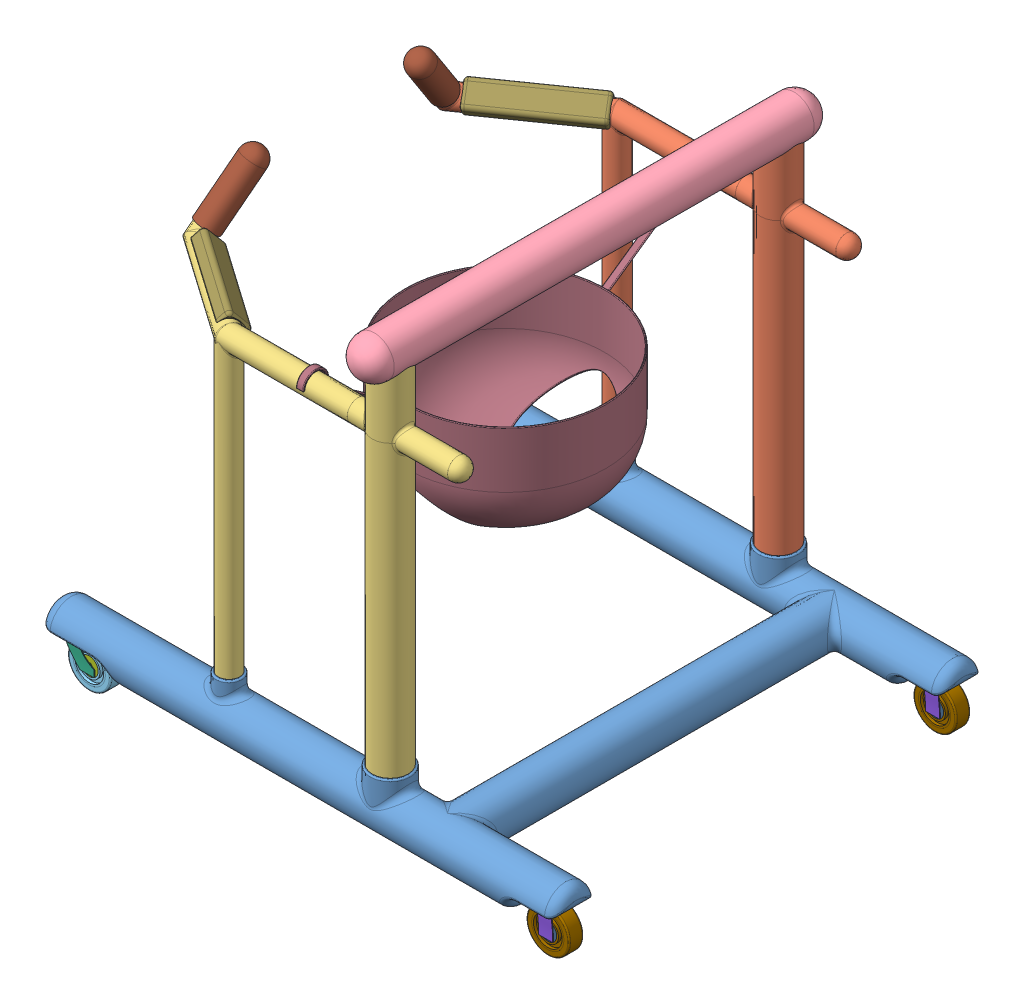
SolidWorks assembly Assem V2 Prototype, configuration Default. Lengths in mm.
Overall size (922.93 824.12 813.04).
41 component instances, 14 part files, 60 mates.
Components (placement in the parent):
- Base V5-1: Base V5 [Default] at (-126.4785 391.078 1010.3536) size (918.71 101.65 765.3)
- Side Left-1: Side Left [Default] at (402.939 968.928 324.5536) x (-1 0 0) z (0 0 -1) size (623.13 766.95 244.49)
- MirrorSide Left-3: MirrorSide Left [Default] at (400.5715 968.928 1010.3536) x (-1 0 0) z (0 0 -1) size (623.13 766.95 244.49)
- TopBarSupport-1: TopBarSupport [Default] at (457.5023 1094.5251 1073.8533) x (0.003452 0 -0.999994) z (0.999994 0 0.003452) size (812.8 71.12 71.12)
- Assem2 Front Wheel-1: Assem2 Front Wheel [Default] at (12.5906 315.4768 322.3492) x (0 0 1) z (-0.999997 0.002364 0) size (53.34 80.1 80.32)
  - Front Wheel-1: Front Wheel [Default] at (-10.3636 34.7825 75.6515) size (25.4 76.2 76.2)
  - Front Wheel Mountv2-1: Front Wheel Mountv2 [Default] at (18.654 50.0525 62.9876) x (1 0 0) z (0 -0.002364 0.999997) size (53.34 52.12 57.51)
  - Front Wheel BearingSet-1: Front Wheel BearingSet [Default] at (-10.3636 34.7825 75.6515) x (0 0.002364 -0.999997) z (1 0 0) size (31.75 31.75 25.4)
- Assem2 Front Wheel-2: Assem2 Front Wheel [Default] at (12.5906 315.4768 1008.1492) x (0 0 1) z (-0.999997 0.002364 0) size (53.34 80.1 80.32)
  - Front Wheel-1: Front Wheel [Default] at (-10.3636 34.7825 75.6515) size (25.4 76.2 76.2)
  - Front Wheel Mountv2-1: Front Wheel Mountv2 [Default] at (18.654 50.0525 62.9876) x (1 0 0) z (0 -0.002364 0.999997) size (53.34 52.12 57.51)
  - Front Wheel BearingSet-1: Front Wheel BearingSet [Default] at (-10.3636 34.7825 75.6515) x (0 0.002364 -0.999997) z (1 0 0) size (31.75 31.75 25.4)
- Assem2 Back Wheel-1: Assem2 Back Wheel [Default] at (706.4816 333.8846 330.834) x (0 0 -1) z (1 0 0) size (53.34 88.94 88.94)
  - Back Wheel Mountv2-1: Back Wheel Mountv2 [Default] at (22.7299 31.7935 30.6399) size (53.34 52.07 26.61)
  - Back Wheel-1: Back Wheel [Default] at (-6.5311 16.5535 43.3399) x (1 0 0) z (0 -0.184287 0.982872) size (25.4 76.2 76.2)
  - BackWheel Bairing Set-1: BackWheel Bairing Set [Default] at (18.8689 16.5535 43.3399) x (0 0 1) z (-1 0 0) size (31.75 31.75 25.4)
- Assem2 Back Wheel-2: Assem2 Back Wheel [Default] at (706.4816 333.8846 1016.634) x (0 0 -1) z (1 0 0) size (53.34 88.94 88.94)
  - Back Wheel Mountv2-1: Back Wheel Mountv2 [Default] at (22.7299 31.7935 30.6399) size (53.34 52.07 26.61)
  - Back Wheel-1: Back Wheel [Default] at (-6.5311 16.5535 43.3399) x (1 0 0) z (0 -0.184287 0.982872) size (25.4 76.2 76.2)
  - BackWheel Bairing Set-1: BackWheel Bairing Set [Default] at (18.8689 16.5535 43.3399) x (0 0 1) z (-1 0 0) size (31.75 31.75 25.4)
- Handle Covering v1-1: Handle Covering v1 [Default] at (-2.516 968.928 448.3888) x (0.979122 -0.193427 -0.062493) z (-0.062493 -0.578988 0.812937) size (43.18 127 43.18)
- Handle Covering v1-2: Handle Covering v1 [Default] at (-4.8834 968.928 886.5185) x (0.979122 -0.193427 0.062493) z (0.062493 0.578988 0.812937) size (43.18 127 43.18)
- Arm Covering v1-1: Arm Covering v1 [Default] at (88.3616 968.928 951.8093) x (0.819152 0 0.573576) z (-0.390769 0.732018 0.558076) size (190.83 24.3 45.72)
- Arm Covering v1-2: Arm Covering v1 [Default] at (92.2038 968.928 382.0653) x (0.819152 0 -0.573576) z (0.446291 -0.62816 0.637369) size (190.83 24.3 45.72)
- ChairPiece-1: ChairPiece [Default] at (318.9986 782.9456 667.2302) x (0 0.001708 0.999999) z (-1 0 0) size (730.43 346.85 355.6)
- WheelScrews-1: WheelScrews [Default] at (-97.2541 392.348 301.6936) x (-0.070113 0 0.997539) z (0.997539 0 0.070113) size (3.81 17.78 3.81)
- WheelScrews-2: WheelScrews [Default] at (-79.4885 392.348 301.6936) x (-0.070113 0 0.997539) z (0.997539 0 0.070113) size (3.81 17.78 3.81)
- WheelScrews-3: WheelScrews [Default] at (-79.4739 392.348 347.4136) x (-0.070113 0 0.997539) z (0.997539 0 0.070113) size (3.81 17.78 3.81)
- WheelScrews-4: WheelScrews [Default] at (-97.2685 392.348 347.4136) x (-0.070113 0 0.997539) z (0.997539 0 0.070113) size (3.81 17.78 3.81)
- WheelScrews-5: WheelScrews [Default] at (-79.4739 392.348 1033.2136) x (-0.070113 0 0.997539) z (0.997539 0 0.070113) size (3.81 17.78 3.81)
- WheelScrews-7: WheelScrews [Default] at (-97.2685 392.348 1033.2136) x (-0.070113 0 0.997539) z (0.997539 0 0.070113) size (3.81 17.78 3.81)
- WheelScrews-8: WheelScrews [Default] at (-79.4885 392.348 987.4936) x (-0.070113 0 0.997539) z (0.997539 0 0.070113) size (3.81 17.78 3.81)
- WheelScrews-9: WheelScrews [Default] at (-97.2541 392.348 987.4936) x (-0.070113 0 0.997539) z (0.997539 0 0.070113) size (3.81 17.78 3.81)
- WheelScrews-10: WheelScrews [Default] at (740.9315 392.348 347.4136) x (-0.837169 0 -0.546944) z (-0.546944 0 0.837169) size (3.81 17.78 3.81)
- WheelScrews-11: WheelScrews [Default] at (758.7115 392.348 347.4136) x (-0.837169 0 -0.546944) z (-0.546944 0 0.837169) size (3.81 17.78 3.81)
- WheelScrews-14: WheelScrews [Default] at (758.7115 392.348 301.6936) x (-0.837169 0 -0.546944) z (-0.546944 0 0.837169) size (3.81 17.78 3.81)
- WheelScrews-15: WheelScrews [Default] at (740.9315 392.348 301.6936) x (-0.837169 0 -0.546944) z (-0.546944 0 0.837169) size (3.81 17.78 3.81)
- WheelScrews-16: WheelScrews [Default] at (740.9315 392.348 1033.2136) x (-0.837169 0 -0.546944) z (-0.546944 0 0.837169) size (3.81 17.78 3.81)
- WheelScrews-18: WheelScrews [Default] at (758.7115 392.348 987.4936) x (-0.837169 0 -0.546944) z (-0.546944 0 0.837169) size (3.81 17.78 3.81)
- WheelScrews-19: WheelScrews [Default] at (740.9315 392.348 987.4936) x (-0.837169 0 -0.546944) z (-0.546944 0 0.837169) size (3.81 17.78 3.81)
- WheelScrews-20: WheelScrews [Default] at (758.7115 392.348 1033.2136) x (-0.837169 0 -0.546944) z (-0.546944 0 0.837169) size (3.81 17.78 3.81)
Mates (geometry in assembly coordinates):
- Tangent1: tangent aligned: cylinder of Base V5-1 through (635.5215 391.078 324.5536) axis (-1 0 0) radius 31.75; sphere of Side Left-1
- Concentric1: concentric aligned: cylinder of Base V5-1 through (460.089 352.977 324.5536) axis (0 1 0) radius 31.75; cylinder of Side Left-1 through (460.089 359.328 324.5536) axis (0 1 0) radius 31.75
- Concentric2: concentric anti-aligned: cylinder of Base V5-1 through (174.339 391.078 324.5536) axis (0 1 0) radius 19.05; cylinder of Side Left-1 through (174.339 968.928 324.5536) axis (0 -1 0) radius 19.05
- Tangent2: tangent aligned: cylinder of Base V5-1 through (635.5215 391.078 1010.3536) axis (-1 0 0) radius 31.75; sphere of MirrorSide Left-3
- Concentric3: concentric aligned: cylinder of Base V5-1 through (457.7215 352.977 1010.3536) axis (0 1 0) radius 31.75; cylinder of MirrorSide Left-3 through (457.7215 359.328 1010.3536) axis (0 1 0) radius 31.75
- Concentric4: concentric anti-aligned: cylinder of Base V5-1 through (171.9715 391.078 1010.3536) axis (0 1 0) radius 19.05; cylinder of MirrorSide Left-3 through (171.9715 968.928 1010.3536) axis (0 -1 0) radius 19.05
- Tangent3: tangent aligned: sphere of MirrorSide Left-3; cylinder of TopBarSupport-1 through (460.2205 1094.5251 286.458) axis (-0.003452 0 0.999994) radius 31.75
- Tangent4: tangent aligned: sphere of Side Left-1; cylinder of TopBarSupport-1 through (460.2205 1094.5251 286.458) axis (-0.003452 0 0.999994) radius 31.75
- Concentric5: concentric aligned: cylinder of MirrorSide Left-3 through (457.7215 968.928 1010.3536) axis (0 1 0) radius 31.75; cylinder of TopBarSupport-1 through (457.7215 1058.9641 1010.3536) axis (0 1 0) radius 31.75
- Concentric6: concentric: sphere of Side Left-1; sphere of Handle Covering v1-1
- Concentric7: concentric anti-aligned: cylinder of Side Left-1 through (-10.1378 937.7174 425.5741) axis (0.193427 0.79206 0.578988) radius 19.05; cylinder of Handle Covering v1-1 through (24.5058 1079.5788 529.2735) axis (-0.193427 -0.79206 -0.578988) radius 19.05
- Concentric8: concentric: sphere of MirrorSide Left-3; sphere of Handle Covering v1-2
- Concentric9: concentric anti-aligned: cylinder of MirrorSide Left-3 through (-12.5053 937.7174 909.3332) axis (0.193427 0.79206 -0.578988) radius 19.05; cylinder of Handle Covering v1-2 through (22.1383 1079.5788 805.6338) axis (-0.193427 -0.79206 0.578988) radius 19.05
- Concentric10: concentric aligned: cylinder of MirrorSide Left-3 through (184.1534 968.928 1018.8835) axis (-0.819152 0 -0.573576) radius 19.05; cylinder of Arm Covering v1-1 through (166.3866 968.928 1006.4431) axis (-0.819152 0 -0.573576) radius 19.05
- Concentric11: concentric aligned: cylinder of Side Left-1 through (186.5208 968.928 316.0238) axis (-0.819152 0 0.573576) radius 19.05; cylinder of Arm Covering v1-2 through (170.2288 968.928 327.4316) axis (-0.819152 0 0.573576) radius 19.05
- Coincident1: coincident anti-aligned: plane of Base V5-1 through (-126.4785 392.348 1010.3536) normal (0 -1 0); plane of Assem2 Front Wheel-1/Front Wheel Mountv2-1 through (-50.2785 392.348 341.0032) normal (0 1 0)
- Coincident2: coincident anti-aligned: plane of Base V5-1 through (-101.0785 392.348 297.8836) normal (0 0 1); plane of Assem2 Front Wheel-1/Front Wheel Mountv2-1 through (-50.2785 365.678 297.8836) normal (0 0 -1)
- Coincident3: coincident anti-aligned: plane of Base V5-1 through (-101.0785 392.348 351.2236) normal (1 0 0); plane of Assem2 Front Wheel-1/Front Wheel Mountv2-1 through (-101.0785 392.348 351.2236) normal (-1 0 0)
- Coincident4: coincident anti-aligned: plane of Base V5-1 through (-126.4785 392.348 1010.3536) normal (0 -1 0); plane of Assem2 Front Wheel-2/Front Wheel Mountv2-1 through (-50.2785 392.348 1026.8032) normal (0 1 0)
- Coincident5: coincident anti-aligned: plane of Base V5-1 through (-101.0785 392.348 1037.0236) normal (1 0 0); plane of Assem2 Front Wheel-2/Front Wheel Mountv2-1 through (-101.0785 392.348 1037.0236) normal (-1 0 0)
- Coincident6: coincident anti-aligned: plane of Base V5-1 through (-101.0785 392.348 1037.0236) normal (0 0 -1); plane of Assem2 Front Wheel-2/Front Wheel Mountv2-1 through (-50.2785 365.678 1037.0236) normal (0 0 1)
- Coincident7: coincident anti-aligned: plane of Base V5-1 through (-126.4785 392.348 1010.3536) normal (0 -1 0); plane of Assem2 Back Wheel-2/Back Wheel Mountv2-1 through (737.1215 392.348 993.9041) normal (0 1 0)
- Coincident8: coincident: plane of Base V5-1 through (762.5215 392.348 1037.0236) normal (-1 0 0); line of Assem2 Back Wheel-2/Back Wheel Mountv2-1 through (762.5215 392.094 983.9376) axis (0 0 1)
- Coincident9: coincident anti-aligned: plane of Base V5-1 through (737.1215 392.348 1037.0236) normal (0 0 -1); plane of Assem2 Back Wheel-2/Back Wheel Mountv2-1 through (737.1215 365.678 1037.0236) normal (0 0 1)
- Coincident10: coincident anti-aligned: plane of Base V5-1 through (-126.4785 392.348 1010.3536) normal (0 -1 0); plane of Assem2 Back Wheel-1/Back Wheel Mountv2-1 through (737.1215 392.348 308.1041) normal (0 1 0)
- Coincident11: coincident: plane of Base V5-1 through (762.5215 392.348 351.2236) normal (-1 0 0); line of Assem2 Back Wheel-1/Back Wheel Mountv2-1 through (762.5215 392.094 298.1376) axis (0 0 1)
- Coincident12: coincident anti-aligned: plane of Base V5-1 through (737.1215 392.348 297.8836) normal (0 0 1); plane of Assem2 Back Wheel-1/Back Wheel Mountv2-1 through (737.1215 365.678 297.8836) normal (0 0 -1)
- Coincident16: coincident anti-aligned: plane of Base V5-1 through (-97.2685 408.858 301.6936) normal (0 -1 0); plane of WheelScrews-1 through (-97.2541 408.858 301.6936) normal (0 1 0)
- Concentric13: concentric aligned: cylinder of Assem2 Front Wheel-1/Front Wheel Mountv2-1 through (-97.2541 340.277 301.6936) axis (0 1 0) radius 1.905; cylinder of WheelScrews-1 through (-97.2541 391.078 301.6936) axis (0 1 0) radius 1.905
- Coincident18: coincident anti-aligned: plane of Base V5-1 through (-79.4885 408.858 301.6936) normal (0 -1 0); plane of WheelScrews-2 through (-79.4885 408.858 301.6936) normal (0 1 0)
- Concentric14: concentric aligned: cylinder of Assem2 Front Wheel-1/Front Wheel Mountv2-1 through (-79.4885 340.277 301.6936) axis (0 1 0) radius 1.905; cylinder of WheelScrews-2 through (-79.4885 391.078 301.6936) axis (0 1 0) radius 1.905
- Coincident19: coincident anti-aligned: plane of Base V5-1 through (-97.2685 408.858 347.4136) normal (0 -1 0); plane of WheelScrews-4 through (-97.2685 408.858 347.4136) normal (0 1 0)
- Concentric15: concentric aligned: cylinder of Assem2 Front Wheel-1/Front Wheel Mountv2-1 through (-97.2685 340.277 347.4136) axis (0 1 0) radius 1.905; cylinder of WheelScrews-4 through (-97.2685 391.078 347.4136) axis (0 1 0) radius 1.905
- Coincident20: coincident anti-aligned: plane of Base V5-1 through (-79.4885 408.858 347.4136) normal (0 -1 0); plane of WheelScrews-3 through (-79.4739 408.858 347.4136) normal (0 1 0)
- Concentric16: concentric aligned: cylinder of Assem2 Front Wheel-1/Front Wheel Mountv2-1 through (-79.4739 340.277 347.4136) axis (0 1 0) radius 1.905; cylinder of WheelScrews-3 through (-79.4739 391.078 347.4136) axis (0 1 0) radius 1.905
- Coincident25: coincident anti-aligned: plane of Base V5-1 through (-97.2685 408.858 987.4936) normal (0 -1 0); plane of WheelScrews-9 through (-97.2541 408.858 987.4936) normal (0 1 0)
- Coincident26: coincident aligned: circle of Assem2 Front Wheel-2/Front Wheel Mountv2-1; cylinder of WheelScrews-9 through (-97.2541 391.078 987.4936) axis (0 1 0) radius 1.905
- Coincident27: coincident anti-aligned: plane of Base V5-1 through (-79.4885 408.858 987.4936) normal (0 -1 0); plane of WheelScrews-8 through (-79.4885 408.858 987.4936) normal (0 1 0)
- Concentric21: concentric aligned: cylinder of Assem2 Front Wheel-2/Front Wheel Mountv2-1 through (-79.4885 340.277 987.4936) axis (0 1 0) radius 1.905; cylinder of WheelScrews-8 through (-79.4885 391.078 987.4936) axis (0 1 0) radius 1.905
- Coincident29: coincident anti-aligned: plane of Base V5-1 through (-97.2685 408.858 1033.2136) normal (0 -1 0); plane of WheelScrews-7 through (-97.2685 408.858 1033.2136) normal (0 1 0)
- Concentric22: concentric aligned: cylinder of Assem2 Front Wheel-2/Front Wheel Mountv2-1 through (-97.2685 340.277 1033.2136) axis (0 1 0) radius 1.905; cylinder of WheelScrews-7 through (-97.2685 391.078 1033.2136) axis (0 1 0) radius 1.905
- Coincident30: coincident anti-aligned: plane of Base V5-1 through (-79.4885 408.858 1033.2136) normal (0 -1 0); plane of WheelScrews-5 through (-79.4739 408.858 1033.2136) normal (0 1 0)
- Concentric23: concentric aligned: cylinder of Assem2 Front Wheel-2/Front Wheel Mountv2-1 through (-79.4739 340.277 1033.2136) axis (0 1 0) radius 1.905; cylinder of WheelScrews-5 through (-79.4739 391.078 1033.2136) axis (0 1 0) radius 1.905
- Coincident31: coincident anti-aligned: plane of Base V5-1 through (758.7115 408.858 347.4136) normal (0 -1 0); plane of WheelScrews-11 through (758.7115 408.858 347.4136) normal (0 1 0)
- Concentric24: concentric aligned: cylinder of Assem2 Back Wheel-1/Back Wheel Mountv2-1 through (758.7115 340.277 347.4136) axis (0 1 0) radius 1.905; cylinder of WheelScrews-11 through (758.7115 391.078 347.4136) axis (0 1 0) radius 1.905
- Coincident32: coincident anti-aligned: plane of Base V5-1 through (740.9315 408.858 347.4136) normal (0 -1 0); circle of WheelScrews-10
- Coincident33: coincident anti-aligned: cylinder of Assem2 Back Wheel-1/Back Wheel Mountv2-1 through (740.9315 340.277 347.4136) axis (0 1 0) radius 1.905; circle of WheelScrews-10
- Coincident36: coincident anti-aligned: plane of Base V5-1 through (758.7115 408.858 301.6936) normal (0 -1 0); plane of WheelScrews-14 through (758.7115 408.858 301.6936) normal (0 1 0)
- Concentric25: concentric aligned: cylinder of Assem2 Back Wheel-1/Back Wheel Mountv2-1 through (758.7115 340.277 301.6936) axis (0 1 0) radius 1.905; cylinder of WheelScrews-14 through (758.7115 391.078 301.6936) axis (0 1 0) radius 1.905
- Coincident37: coincident anti-aligned: plane of Base V5-1 through (740.9315 408.858 301.6936) normal (0 -1 0); plane of WheelScrews-15 through (740.9315 408.858 301.6936) normal (0 1 0)
- Concentric26: concentric aligned: cylinder of Assem2 Back Wheel-1/Back Wheel Mountv2-1 through (740.9315 340.277 301.6936) axis (0 1 0) radius 1.905; cylinder of WheelScrews-15 through (740.9315 391.078 301.6936) axis (0 1 0) radius 1.905
- Coincident38: coincident anti-aligned: plane of Base V5-1 through (758.7115 408.858 1033.2136) normal (0 -1 0); plane of WheelScrews-20 through (758.7115 408.858 1033.2136) normal (0 1 0)
- Concentric27: concentric aligned: cylinder of Assem2 Back Wheel-2/Back Wheel Mountv2-1 through (758.7115 340.277 1033.2136) axis (0 1 0) radius 1.905; cylinder of WheelScrews-20 through (758.7115 391.078 1033.2136) axis (0 1 0) radius 1.905
- Coincident39: coincident anti-aligned: plane of Base V5-1 through (740.9315 408.858 1033.2136) normal (0 -1 0); plane of WheelScrews-16 through (740.9315 408.858 1033.2136) normal (0 1 0)
- Concentric28: concentric aligned: cylinder of Assem2 Back Wheel-2/Back Wheel Mountv2-1 through (740.9315 340.277 1033.2136) axis (0 1 0) radius 1.905; cylinder of WheelScrews-16 through (740.9315 391.078 1033.2136) axis (0 1 0) radius 1.905
- Coincident40: coincident anti-aligned: plane of Base V5-1 through (758.7115 408.858 987.4936) normal (0 -1 0); plane of WheelScrews-18 through (758.7115 408.858 987.4936) normal (0 1 0)
- Concentric29: concentric aligned: cylinder of Assem2 Back Wheel-2/Back Wheel Mountv2-1 through (758.7115 340.277 987.4936) axis (0 1 0) radius 1.905; cylinder of WheelScrews-18 through (758.7115 391.078 987.4936) axis (0 1 0) radius 1.905
- Coincident41: coincident anti-aligned: plane of Base V5-1 through (740.9315 408.858 987.4936) normal (0 -1 0); plane of WheelScrews-19 through (740.9315 408.858 987.4936) normal (0 1 0)
- Concentric30: concentric aligned: cylinder of Assem2 Back Wheel-2/Back Wheel Mountv2-1 through (740.9315 340.277 987.4936) axis (0 1 0) radius 1.905; cylinder of WheelScrews-19 through (740.9315 391.078 987.4936) axis (0 1 0) radius 1.905
- Concentric39: concentric aligned: cylinder of Side Left-1 through (402.939 968.928 324.5536) axis (-1 0 0) radius 19.05; cylinder of ChairPiece-1 through (496.7996 968.928 324.5536) axis (-1 0 0) radius 19.05
